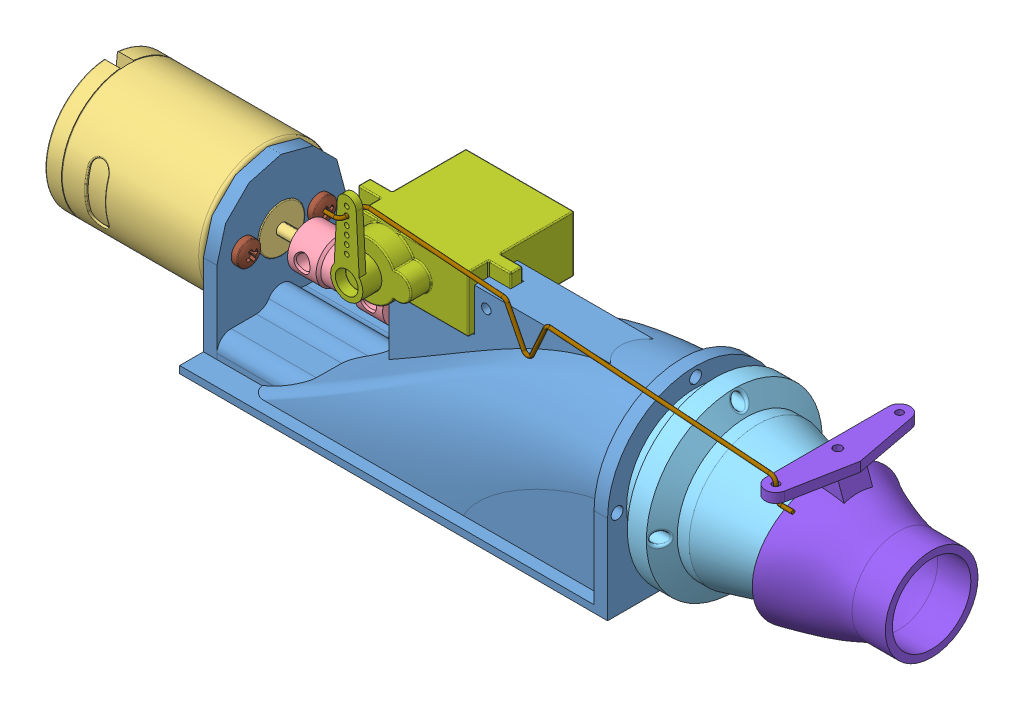
SolidWorks assembly assembly 25mm impeller jet drive, configuration Default. Lengths in mm.
Overall size (175.66 47.97 37.3).
16 component instances, 13 part files, 33 mates.
Components (placement in the parent):
- jet drive for 25mm impeller-1: jet drive for 25mm impeller [Default] at (-2.105 -21.3255 0) size (90 39.15 37)
- shaft-1: shaft [Default] at (-69.955 -0.679 0) x (1 0 0) z (0 -0.374675 0.927156) size (85 3 3)
- RS365 DC Motor-1: RS365 DC Motor [Default] at (-77.105 -0.679 0) x (1 0 0) z (0 1 0) size (51 27.5 27.5)
- shaft coupler-1: shaft coupler [Default] at (-63.411 -0.679 0) x (-1 0 0) z (0 -0.042922 -0.999078) size (20 9 9)
- stator-1: stator [Default] at (-4.955 -0.679 0) size (35.93 37.32 37.3)
- impeller 25min OD-1: impeller 25min OD [Default] at (11.045 -0.679 0) x (0 0.907746 0.419521) z (0 -0.419521 0.907746) size (24.22 20 24.19)
- servo towerpro sg90-1: servo towerpro sg90 [Default] at (-55.63 10.746 -16.6125) x (1 0 0) z (0 -1 0) size (32.05 31 21.88)
- nozzle-1: nozzle [Default] at (25.545 -0.679 0) x (0 0 -1) z (0 -1 0) size (31.46 22.02 31.51)
- wire-1: wire [Default] at origin size (95.63 10.1 6.02)
- bearing-1: bearing [Default] at (-48.4939 -0.679 0) x (0 -0.407486 -0.913211) z (-1 0 0) size (4 4 4)
- bearing-2: bearing [Default] at (-58.105 -0.679 0) x (0 0.170235 0.985404) z (-1 0 0) size (4 4 4)
- bearing-3: bearing [Default] at (15.045 -0.679 0) x (0 0.944365 0.328901) z (-1 0 0) size (4 4 4)
- hull-1: hull [Default] at origin size (333.75 30.44 61.92) (hidden)
- pan head cross recess screw_iso-1: pan head cross recess screw_iso [ISO 7045 - M2.5 x 5 - Z - 5N] at (-87.155 -0.679 8) x (-1 0 0) z (0 -0.924225 -0.381849) size (7.05 5 5)
- pan head cross recess screw_iso-2: pan head cross recess screw_iso [ISO 7045 - M2.5 x 5 - Z - 5N] at (-87.155 -0.679 -8) x (-1 0 0) z (0 -0.85199 -0.523557) size (7.05 5 5)
- countersunk flat head cross recess screw_iso-2: countersunk flat head cross recess screw_iso [ISO 7046-1 - M2.5 x 5 - Z - 5N] at (-92.105 -13.679 0) size (5 4.7 4.7)
Mates (geometry in assembly coordinates):
- Coincident1: coincident aligned: line of jet drive for 25mm impeller-1 through (-89.255 -0.679 0) axis (-1 0 0); line of 2.3mm shaft-1 through (15.045 -0.679 0) axis (-1 0 0)
- Coincident5: coincident anti-aligned: line of 2.3mm shaft-1 through (15.045 -0.679 0) axis (-1 0 0); line of shaft coupler 2.3mm aliexpress-1 through (-76.911 -0.679 0) axis (1 0 0)
- Coincident6: coincident anti-aligned: line of 2.3mm shaft-1 through (15.045 -0.679 0) axis (-1 0 0); line of stator-1 through (11.045 -0.679 0) axis (1 0 0)
- Coincident7: coincident anti-aligned: plane of jet drive for 25mm impeller-1 through (-4.955 -0.679 0) normal (1 0 0); plane of stator-1 through (-4.955 -0.679 -14.5) normal (-1 0 0)
- Coincident8: coincident anti-aligned: line of 2.3mm shaft-1 through (15.045 -0.679 0) axis (-1 0 0); line of impeller 25min OD-1 through (-1.955 -0.679 0) axis (1 0 0)
- Coincident9: coincident anti-aligned: plane of jet drive for 25mm impeller-1 through (-2.104 4.821 -4.5) normal (0 1 0); plane of servo towerpro sg90-1 through (-55.63 4.821 -16.6125) normal (0 -1 0)
- Coincident10: coincident aligned: line of 2.3mm shaft-1 through (15.045 -0.679 0) axis (-1 0 0); line of nozzle-1 through (47.545 -0.679 0) axis (-1 0 0)
- Parallel1: parallel aligned: plane of nozzle-1 through (27.795 17.821 13) normal (0 1 0)
- Coincident11: coincident anti-aligned: line of stator-1 through (27.795 -11.679 0) axis (0 1 0); line of nozzle-1 through (27.795 17.821 0) axis (0 -1 0)
- Coincident12: coincident anti-aligned: line of 2.3mm shaft-1 through (15.045 -0.679 0) axis (-1 0 0); line of bearing-1 through (-52.4939 -0.679 0) axis (1 0 0)
- Coincident13: coincident anti-aligned: line of 2.3mm shaft-1 through (15.045 -0.679 0) axis (-1 0 0); line of bearing-2 through (-62.105 -0.679 0) axis (1 0 0)
- Coincident14: coincident anti-aligned: line of 2.3mm shaft-1 through (15.045 -0.679 0) axis (-1 0 0); line of bearing-3 through (11.045 -0.679 0) axis (1 0 0)
- Coincident15: coincident anti-aligned: plane of stator-1 through (11.045 -0.679 0) normal (-1 0 0); plane of impeller 25min OD-1 through (11.045 3.8598 2.0976) normal (1 0 0)
- Coincident16: coincident anti-aligned: plane of jet drive for 25mm impeller-1 through (-58.105 -2.679 0) normal (-1 0 0); plane of bearing-2 through (-58.105 -0.679 0) normal (1 0 0)
- Coincident17: coincident anti-aligned: plane of jet drive for 25mm impeller-1 through (-52.4939 -2.179 0) normal (1 0 0); plane of bearing-1 through (-52.4939 -0.679 0) normal (-1 0 0)
- Coincident18: coincident anti-aligned: plane of bearing-3 through (11.045 -0.679 0) normal (-1 0 0); plane of impeller 25min OD-1 through (11.045 3.8598 2.0976) normal (1 0 0)
- Coincident22: coincident anti-aligned: line of jet drive for 25mm impeller-1 through (-89.255 -0.679 8) axis (-1 0 0); line of RS365 DC Motor-1 through (-96.855 -0.679 8) axis (1 0 0)
- Coincident23: coincident anti-aligned: line of jet drive for 25mm impeller-1 through (-89.255 -0.679 -8) axis (-1 0 0); line of RS365 DC Motor-1 through (-96.855 -0.679 -8) axis (1 0 0)
- Coincident24: coincident anti-aligned: plane of jet drive for 25mm impeller-1 through (-92.105 -21.3255 18.5) normal (-1 0 0); plane of RS365 DC Motor-1 through (-92.105 -0.679 -4.95) normal (1 0 0)
- Coincident26: coincident anti-aligned: plane of jet drive for 25mm impeller-1 through (-39.605 -21.3255 0) normal (-1 0 0); plane of servo towerpro sg90-1 through (-39.605 4.821 -1.1125) normal (1 0 0)
- Coincident32: coincident anti-aligned: plane of jet drive for 25mm impeller-1 through (-44.105 13.821 1.3875) normal (0 0 -1); plane of servo towerpro sg90-1 through (-39.605 4.821 1.3875) normal (0 0 1)
- Coincident33: coincident: plane of jet drive for 25mm impeller-1 through (-2.105 -21.3255 0) normal (0 0 1)
- Coincident34: coincident aligned: plane of 2.3mm shaft-1 through (15.045 -0.679 0) normal (1 0 0); plane of bearing-3 through (15.045 -0.679 0) normal (1 0 0)
- Coincident35: coincident anti-aligned: line of jet drive for 25mm impeller-1 through (-55.2994 3.821 0) axis (0 1 0); line of screw servo-1 through (-55.2994 3.321 0) axis (0 -1 0)
- Coincident36: coincident anti-aligned: plane of jet drive for 25mm impeller-1 through (-55.2994 3.821 0) normal (0 1 0); plane of screw servo-1 through (-54.2994 3.321 0) normal (0 -1 0)
- Coincident37: coincident aligned: line of jet drive for 25mm impeller-1 through (-41.605 10.746 1.3875) axis (0 0 1); line of screw servo-2 through (-41.605 10.746 4.5) axis (0 0 -1)
- Coincident38: coincident anti-aligned: plane of jet drive for 25mm impeller-1 through (-2.104 4.821 4.5) normal (0 0 1); circle of screw servo-2
- Coincident39: coincident anti-aligned: line of jet drive for 25mm impeller-1 through (-89.255 -0.679 8) axis (-1 0 0); line of pan head cross recess screw_iso-1 through (-92.5233 -0.679 8) axis (1 0 0)
- Coincident40: coincident anti-aligned: plane of jet drive for 25mm impeller-1 through (-89.255 -0.679 0) normal (1 0 0); plane of pan head cross recess screw_iso-1 through (-89.255 -0.2016 6.8447) normal (-1 0 0)
- Coincident41: coincident anti-aligned: line of jet drive for 25mm impeller-1 through (-89.255 -0.679 -8) axis (-1 0 0); line of pan head cross recess screw_iso-2 through (-92.5233 -0.679 -8) axis (1 0 0)
- Coincident42: coincident anti-aligned: plane of jet drive for 25mm impeller-1 through (-89.255 -0.679 0) normal (1 0 0); plane of pan head cross recess screw_iso-2 through (-89.255 -0.0245 -9.065) normal (-1 0 0)
- Coincident43: coincident aligned: line of jet drive for 25mm impeller-1 through (-84.9763 -13.679 0) axis (-1 0 0); line of countersunk flat head cross recess screw_iso-2 through (-87.105 -13.679 0) axis (-1 0 0)
- Coincident44: coincident aligned: plane of countersunk flat head cross recess screw_iso-2 through (-92.105 -13.679 0) normal (-1 0 0); plane of jet drive for 25mm impeller-1 through (-92.105 -0.679 0) normal (-1 0 0)
